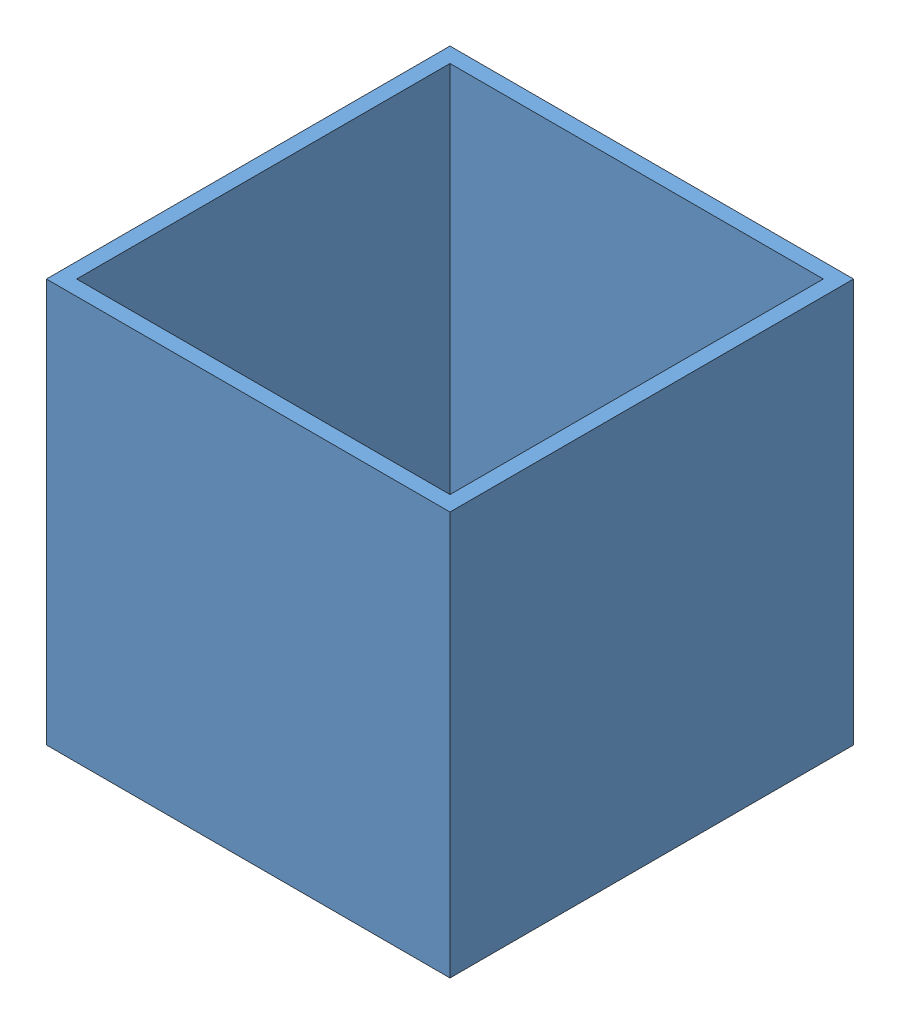
SolidWorks assembly Assem2, configuration Default. Lengths in mm.
Overall size (80 90 80).
2 component instances, 2 part files, 5 mates.
Components (placement in the parent):
- Part1^Assem2-1: Part1^Assem2 [Default] at origin size (80 90 80)
- Part2^Assem2-2: Part2^Assem2 [Default] at (-14.2381 3 -55.4822) x (-0.873481 0 0.486858) z (0 1 0) size (43.94 23.54 2)
Mates (geometry in assembly coordinates):
- InPlace1: in place: plane of Part1^Assem2-1 through (0 0 0) normal (0 0 1); moOrthogonalPlaneRef_w of Part1^Assem2-1 through (0 0 0) normal (0 1 0); plane of Part1^Assem2-1 through (0 0 0) normal (1 0 0); unknown of Part1^Assem2-1
- Coincident1: coincident aligned: 
- Coincident2: coincident aligned: plane of Part1^Assem2-1 through (0 0 0) normal (0 1 0)
- Coincident3: coincident anti-aligned: plane of Part1^Assem2-1 through (0 0 0) normal (1 0 0)
- Coincident7: coincident anti-aligned: plane of Part1^Assem2-1 through (0 3 0) normal (0 1 0); plane of Part2^Assem2-2 through (46.8082 3 -43.7143) normal (0 -1 0)
